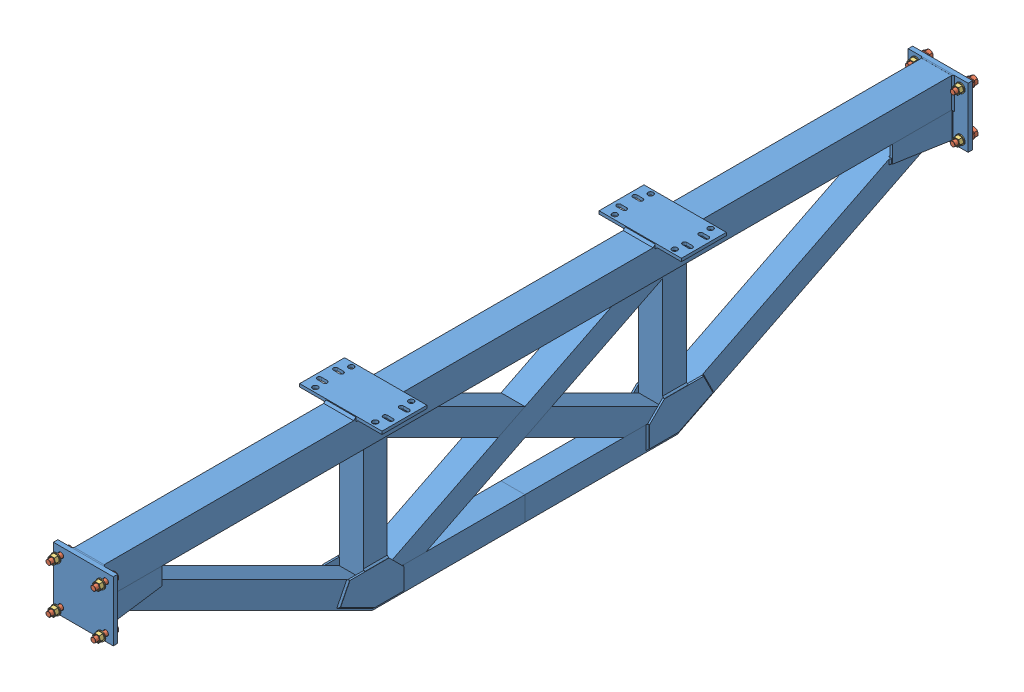
SolidWorks assembly 0403-FRAME 1 ASSEMBLAGE, configuration Predeterminado. Lengths in mm.
Overall size (275 600 2943).
17 component instances, 3 part files, 16 mates.
Components (placement in the parent):
- 0411-FRAME 1-1: 0411-FRAME 1 [Predeterminado<Como mecanizada>] at (-16.9752 310.8714 0) size (275 600 2870)
- M-16x60 DIN-6914-18 and DIN-6916-1: M-16x60 DIN-6914-18 and DIN-6916 [DIN 6914 - M20 x 65 x 31-N] at (58.0248 335.8714 1404) x (0 0 1) z (-0.381849 -0.924225 0) size (73 30 30)
- M-16x60 DIN-6914-18 and DIN-6916-15: M-16x60 DIN-6914-18 and DIN-6916 [DIN 6914 - M20 x 65 x 31-N] at (58.0248 185.8714 1404) x (0 0 1) z (-0.381849 -0.924225 0) size (73 30 30)
- M-16x60 DIN-6914-18 and DIN-6916-17: M-16x60 DIN-6914-18 and DIN-6916 [DIN 6914 - M20 x 65 x 31-N] at (-91.9752 335.8714 1404) x (0 0 1) z (-0.381849 -0.924225 0) size (73 30 30)
- M-16x60 DIN-6914-18 and DIN-6916-19: M-16x60 DIN-6914-18 and DIN-6916 [DIN 6914 - M20 x 65 x 31-N] at (-91.9752 185.8714 1404) x (0 0 1) z (-0.381849 -0.924225 0) size (73 30 30)
- M-16 DIN-6915 and DIN-6916-1: M-16 DIN-6915 and DIN-6916 [Hexagon Nut DIN 6915 - M20 - N] at (-91.9752 335.8714 1453) x (-0.923728 -0.383049 0) z (0 0 -1) size (30 30 16)
- M-16 DIN-6915 and DIN-6916-17: M-16 DIN-6915 and DIN-6916 [Hexagon Nut DIN 6915 - M20 - N] at (58.0248 335.8714 1453) x (-0.923728 -0.383049 0) z (0 0 -1) size (30 30 16)
- M-16 DIN-6915 and DIN-6916-19: M-16 DIN-6915 and DIN-6916 [Hexagon Nut DIN 6915 - M20 - N] at (58.0248 185.8714 1453) x (-0.923728 -0.383049 0) z (0 0 -1) size (30 30 16)
- M-16 DIN-6915 and DIN-6916-21: M-16 DIN-6915 and DIN-6916 [Hexagon Nut DIN 6915 - M20 - N] at (-91.9752 185.8714 1453) x (-0.923728 -0.383049 0) z (0 0 -1) size (30 30 16)
- M-16x60 DIN-6914-18 and DIN-6916-20: M-16x60 DIN-6914-18 and DIN-6916 [DIN 6914 - M20 x 65 x 31-N] at (-91.9752 335.8714 -1466) x (0 0 1) z (-0.381849 -0.924225 0) size (73 30 30)
- M-16x60 DIN-6914-18 and DIN-6916-21: M-16x60 DIN-6914-18 and DIN-6916 [DIN 6914 - M20 x 65 x 31-N] at (58.0248 335.8714 -1466) x (0 0 1) z (-0.381849 -0.924225 0) size (73 30 30)
- M-16x60 DIN-6914-18 and DIN-6916-22: M-16x60 DIN-6914-18 and DIN-6916 [DIN 6914 - M20 x 65 x 31-N] at (-91.9752 185.8714 -1466) x (0 0 1) z (-0.381849 -0.924225 0) size (73 30 30)
- M-16x60 DIN-6914-18 and DIN-6916-23: M-16x60 DIN-6914-18 and DIN-6916 [DIN 6914 - M20 x 65 x 31-N] at (58.0248 185.8714 -1466) x (0 0 1) z (-0.381849 -0.924225 0) size (73 30 30)
- M-16 DIN-6915 and DIN-6916-20: M-16 DIN-6915 and DIN-6916 [Hexagon Nut DIN 6915 - M20 - N] at (58.0248 185.8714 -1417) x (-0.923728 -0.383049 0) z (0 0 -1) size (30 30 16)
- M-16 DIN-6915 and DIN-6916-22: M-16 DIN-6915 and DIN-6916 [Hexagon Nut DIN 6915 - M20 - N] at (-91.9752 185.8714 -1417) x (-0.923728 -0.383049 0) z (0 0 -1) size (30 30 16)
- M-16 DIN-6915 and DIN-6916-18: M-16 DIN-6915 and DIN-6916 [Hexagon Nut DIN 6915 - M20 - N] at (58.0248 335.8714 -1417) x (-0.923728 -0.383049 0) z (0 0 -1) size (30 30 16)
- M-16 DIN-6915 and DIN-6916-16: M-16 DIN-6915 and DIN-6916 [Hexagon Nut DIN 6915 - M20 - N] at (-91.9752 335.8714 -1417) x (-0.923728 -0.383049 0) z (0 0 -1) size (30 30 16)
Mates (geometry in assembly coordinates):
- Coincidente1: coincident anti-aligned: plane of 0411-FRAME 1-1 through (83.0248 160.8714 1420) normal (0 0 -1); plane of M-16x60 DIN-6914-18 and DIN-6916-1 through (58.0248 335.8714 1420) normal (0 0 1)
- Concéntrica1: concentric aligned: cylinder of 0411-FRAME 1-1 through (58.0248 335.8714 1435) axis (0 0 -1) radius 9; cylinder of M-16x60 DIN-6914-18 and DIN-6916-1 through (58.0248 335.8714 1404) axis (0 0 -1) radius 8
- Coincidente2: coincident anti-aligned: plane of 0411-FRAME 1-1 through (83.0248 160.8714 1420) normal (0 0 -1); plane of M-16x60 DIN-6914-18 and DIN-6916-15 through (58.0248 185.8714 1420) normal (0 0 1)
- Concéntrica2: concentric aligned: cylinder of 0411-FRAME 1-1 through (58.0248 185.8714 1435) axis (0 0 -1) radius 9; cylinder of M-16x60 DIN-6914-18 and DIN-6916-15 through (58.0248 185.8714 1404) axis (0 0 -1) radius 8
- Coincidente3: coincident anti-aligned: plane of 0411-FRAME 1-1 through (83.0248 160.8714 1420) normal (0 0 -1); plane of M-16x60 DIN-6914-18 and DIN-6916-17 through (-91.9752 335.8714 1420) normal (0 0 1)
- Concéntrica3: concentric aligned: cylinder of 0411-FRAME 1-1 through (-91.9752 335.8714 1435) axis (0 0 -1) radius 9; cylinder of M-16x60 DIN-6914-18 and DIN-6916-17 through (-91.9752 335.8714 1404) axis (0 0 -1) radius 8
- Coincidente4: coincident anti-aligned: plane of 0411-FRAME 1-1 through (83.0248 160.8714 1420) normal (0 0 -1); plane of M-16x60 DIN-6914-18 and DIN-6916-19 through (-91.9752 185.8714 1420) normal (0 0 1)
- Concéntrica4: concentric aligned: cylinder of 0411-FRAME 1-1 through (-91.9752 185.8714 1435) axis (0 0 -1) radius 9; cylinder of M-16x60 DIN-6914-18 and DIN-6916-19 through (-91.9752 185.8714 1404) axis (0 0 -1) radius 8
- Distancia1: distance = 15 mm anti-aligned: plane of 0411-FRAME 1-1 through (83.0248 160.8714 1435) normal (0 0 1); plane of M-16 DIN-6915 and DIN-6916-1 through (-91.9752 335.8714 1450) normal (0 0 -1)
- Concéntrica5: concentric aligned: cylinder of M-16x60 DIN-6914-18 and DIN-6916-17 through (-91.9752 335.8714 1404) axis (0 0 -1) radius 8; cylinder of M-16 DIN-6915 and DIN-6916-1 through (-91.9752 335.8714 1466) axis (0 0 -1) radius 8
- Distancia2: distance = 15 mm anti-aligned: plane of 0411-FRAME 1-1 through (83.0248 160.8714 1435) normal (0 0 1); plane of M-16 DIN-6915 and DIN-6916-17 through (58.0248 335.8714 1450) normal (0 0 -1)
- Concéntrica6: concentric aligned: cylinder of M-16x60 DIN-6914-18 and DIN-6916-1 through (58.0248 335.8714 1404) axis (0 0 -1) radius 8; cylinder of M-16 DIN-6915 and DIN-6916-17 through (58.0248 335.8714 1466) axis (0 0 -1) radius 8
- Distancia3: distance = 15 mm anti-aligned: plane of 0411-FRAME 1-1 through (83.0248 160.8714 1435) normal (0 0 1); plane of M-16 DIN-6915 and DIN-6916-19 through (58.0248 185.8714 1450) normal (0 0 -1)
- Concéntrica7: concentric aligned: cylinder of M-16x60 DIN-6914-18 and DIN-6916-15 through (58.0248 185.8714 1404) axis (0 0 -1) radius 8; cylinder of M-16 DIN-6915 and DIN-6916-19 through (58.0248 185.8714 1466) axis (0 0 -1) radius 8
- Distancia4: distance = 15 mm anti-aligned: plane of 0411-FRAME 1-1 through (83.0248 160.8714 1435) normal (0 0 1); plane of M-16 DIN-6915 and DIN-6916-21 through (-91.9752 185.8714 1450) normal (0 0 -1)
- Concéntrica8: concentric aligned: cylinder of M-16x60 DIN-6914-18 and DIN-6916-19 through (-91.9752 185.8714 1404) axis (0 0 -1) radius 8; cylinder of M-16 DIN-6915 and DIN-6916-21 through (-91.9752 185.8714 1466) axis (0 0 -1) radius 8
